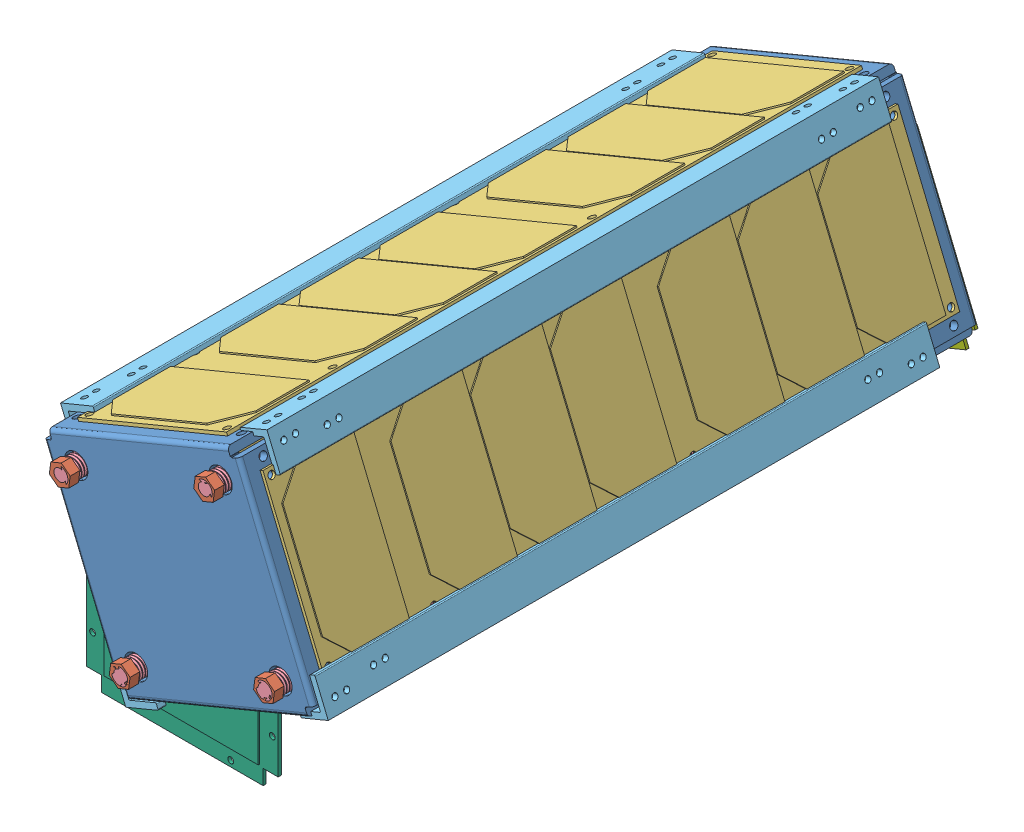
SolidWorks assembly RADIO, configuration Default. Lengths in mm.
Overall size (151.59 158.02 364.24).
20 component instances, 7 part files, 36 mates.
Components (placement in the parent):
- Top Plate-2: Top Plate [Default] at (19.1379 139.3063 372.2212) x (-0.923728 -0.383049 0) z (0 0 -1) size (108 108 34)
- Nut-9: Nut [Default] at (90.7698 196.7391 380.6212) x (-0.923728 -0.383049 0) z (0 0 -1) size (11.55 10 5.32)
- Nut-10: Nut [Default] at (47.5155 92.197 380.6212) x (-0.923728 -0.383049 0) z (0 0 -1) size (11.55 10 5.32)
- Nut-11: Nut [Default] at (16.8715 166.0952 380.6212) x (-0.923728 -0.383049 0) z (0 0 -1) size (11.55 10 5.32)
- Nut-12: Nut [Default] at (121.4137 122.8409 380.6212) x (-0.923728 -0.383049 0) z (0 0 -1) size (11.55 10 5.32)
- 3U Panel-1: 3U Panel [Default] at (98.8495 213.8036 288.4357) x (-0.383049 0.923728 0) z (0.923728 0.383049 0) size (82.6 325 2.3)
- Threaded Rod-6: Threaded Rod [Default] at (90.7698 196.7391 38.6212) x (0 0 1) z (-1 0 0) size (343.27 11.61 10.3)
- Support-2: Support [Default] at (142.8836 118.0572 76.5784) x (-0.383049 0.923728 0) z (-0.923728 -0.383049 0) size (18 313 15)
- Threaded Rod-7: Threaded Rod [Default] at (16.8715 166.0952 38.6212) x (0 0 1) z (-0.923728 -0.383049 0) size (343.27 11.61 10.3)
- Threaded Rod-8: Threaded Rod [Default] at (47.5155 92.197 380.6212) x (0 0 -1) z (0.923728 0.383049 0) size (343.27 11.61 10.3)
- Threaded Rod-9: Threaded Rod [Default] at (121.4137 122.8409 380.6212) x (0 0 -1) z (0.923728 0.383049 0) size (343.27 11.61 10.3)
- Support-3: Support [Default] at (42.7318 70.727 76.5784) x (0.923728 0.383049 0) z (-0.383049 0.923728 0) size (18 313 15)
- Support-4: Support [Default] at (-1.7019 177.8795 339.8641) x (0.923728 0.383049 0) z (0.383049 -0.923728 0) size (18 313 15)
- Support-5: Support [Default] at (102.554 215.3126 339.8641) x (0.383049 -0.923728 0) z (-0.923728 -0.383049 0) size (18 313 15)
- 3U Panel-2: 3U Panel [Default] at (137.8653 116.2391 288.4357) x (0.923728 0.383049 0) z (0.383049 -0.923728 0) size (82.6 325 2.3)
- 3U Panel-3: 3U Panel [Default] at (39.4357 75.1325 288.4357) x (0.383049 -0.923728 0) z (-0.923728 -0.383049 0) size (82.6 325 2.3)
- 3U Panel-4: 3U Panel [Default] at (-0.1929 174.175 288.4357) x (-0.923728 -0.383049 0) z (-0.383049 0.923728 0) size (82.6 325 2.3)
- 1U Panel-1: 1U Panel [Default] at (88.2857 119.3168 363.766) size (98 98 2.3)
- Top Plate-3: Top Plate [Default] at (108.1262 176.2077 31.6212) x (0.923728 0.383049 0) z (0 0 1) size (108 108 34)
- Nanocom Antenna-1: Nanocom Antenna [Default] at (54.919 102.7093 23.6212) x (-0.923728 -0.383049 0) z (0 0 -1) size (98 98 11)
Mates (geometry in assembly coordinates):
- Coincident19: coincident: plane of Top Plate-2 through (19.1379 139.3063 372.2212) normal (0 0 1); plane of Nut-9 through (90.7698 196.7391 372.2212) normal (0 0 -1)
- Coincident20: coincident: plane of Top Plate-2 through (19.1379 139.3063 372.2212) normal (0 0 1); plane of Nut-11 through (16.8715 166.0952 372.2212) normal (0 0 -1)
- Coincident21: coincident: plane of Top Plate-2 through (19.1379 139.3063 372.2212) normal (0 0 1); plane of Nut-10 through (47.5155 92.197 372.2212) normal (0 0 -1)
- Coincident22: coincident: plane of Top Plate-2 through (19.1379 139.3063 372.2212) normal (0 0 1); plane of Nut-12 through (121.4137 122.8409 372.2212) normal (0 0 -1)
- Concentric13: concentric: circle of Top Plate-2; circle of Nut-9
- Concentric14: concentric: circle of Top Plate-2; circle of Nut-11
- Concentric15: concentric: circle of Top Plate-2; circle of Nut-10
- Concentric16: concentric: circle of Top Plate-2; circle of Nut-12
- Concentric31: concentric: circle of Nut-9; circle of Threaded Rod-6
- Coincident39: coincident: plane of Nut-9 through (90.7698 196.7391 380.6212) normal (0 0 1); plane of Threaded Rod-6 through (90.7698 196.7391 380.6212) normal (0 0 1)
- Coincident42: coincident: plane of Top Plate-2 through (113.5133 178.4416 338.2212) normal (0.923728 0.383049 0); plane of 3U Panel-1 through (98.8495 213.8036 288.4357) normal (-0.923728 -0.383049 0)
- Concentric33: concentric: circle of Top Plate-2; circle of 3U Panel-1
- Coincident46: coincident: circle of Top Plate-2; circle of Support-2
- Parallel6: parallel: line of Top Plate-2 through (135.5518 113.5477 338.2212) axis (0 0 1); line of Support-2 through (144.9357 113.1087 46.2212) axis (0 0 1)
- Coincident48: coincident: plane of Nut-11 through (16.8715 166.0952 380.6212) normal (0 0 1); plane of Threaded Rod-7 through (16.8715 166.0952 380.6212) normal (0 0 1)
- Concentric34: concentric: circle of Nut-11; circle of Threaded Rod-7
- Coincident49: coincident: plane of Nut-10 through (47.5155 92.197 380.6212) normal (0 0 1); plane of Threaded Rod-8 through (47.5155 92.197 380.6212) normal (0 0 1)
- Concentric35: concentric: circle of Nut-10; circle of Threaded Rod-8
- Coincident50: coincident: plane of Nut-12 through (121.4137 122.8409 380.6212) normal (0 0 1); plane of Threaded Rod-9 through (121.4137 122.8409 380.6212) normal (0 0 1)
- Concentric36: concentric: circle of Nut-12; circle of Threaded Rod-9
- Coincident51: coincident: circle of Top Plate-2; circle of Support-3
- Coincident52: coincident: circle of Top Plate-2; circle of Support-4
- Parallel7: parallel: line of Top Plate-2 through (0.3004 169.508 338.2212) axis (0 0 1); line of Support-4 through (-6.6505 175.8274 370.2212) axis (0 0 -1)
- Parallel8: parallel: line of Support-3 through (37.7832 68.675 46.2212) axis (0 0 1); line of Support-4 through (-0.5217 161.0478 46.2212) axis (0 0 1)
- Coincident55: coincident: circle of Top Plate-2; circle of Support-5
- Parallel9: parallel: line of Top Plate-2 through (94.1825 213.3103 338.2212) axis (0 0 1); line of Support-5 through (100.502 220.2611 370.2212) axis (0 0 -1)
- Coincident57: coincident: circle of Top Plate-2; circle of 3U Panel-2
- Parallel10: parallel: line of 3U Panel-2 through (127.9772 110.4067 364.4212) axis (-0.923728 -0.383049 0); line of Top Plate-2 through (135.5518 113.5477 370.2212) axis (-0.923728 -0.383049 0)
- Coincident59: coincident: circle of Top Plate-2; circle of 3U Panel-4
- Parallel12: parallel: line of Top Plate-2 through (2.7334 175.3885 370.2212) axis (0.923728 0.383049 0); line of 3U Panel-4 through (9.6951 180.0074 364.4212) axis (0.923728 0.383049 0)
- Coincident62: coincident: circle of Top Plate-2; circle of 3U Panel-3
- Parallel13: parallel: line of 3U Panel-3 through (33.6033 85.0206 364.4212) axis (-0.383049 0.923728 0); line of Top Plate-2 through (38.2222 78.0589 370.2212) axis (-0.383049 0.923728 0)
- Coincident64: coincident: circle of 3U Panel-1; circle of Top Plate-3
- Distance6: distance = 5 mm: plane of Nanocom Antenna-1 through (54.919 102.7093 26.6212) normal (0 0 1); plane of Top Plate-3 through (108.1262 176.2077 31.6212) normal (0 0 -1)
- Parallel15: parallel: line of Top Plate-3 through (3.4995 173.541 31.6212) axis (0.923728 0.383049 0); line of Nanocom Antenna-1 through (11.4005 156.0215 22.1212) axis (0.923728 0.383049 0)
- Parallel16: parallel: line of 3U Panel-1 through (136.3218 127.6156 39.4212) axis (-0.383049 0.923728 0); line of Top Plate-3 through (137.9849 119.4282 33.6212) axis (-0.383049 0.923728 0)
